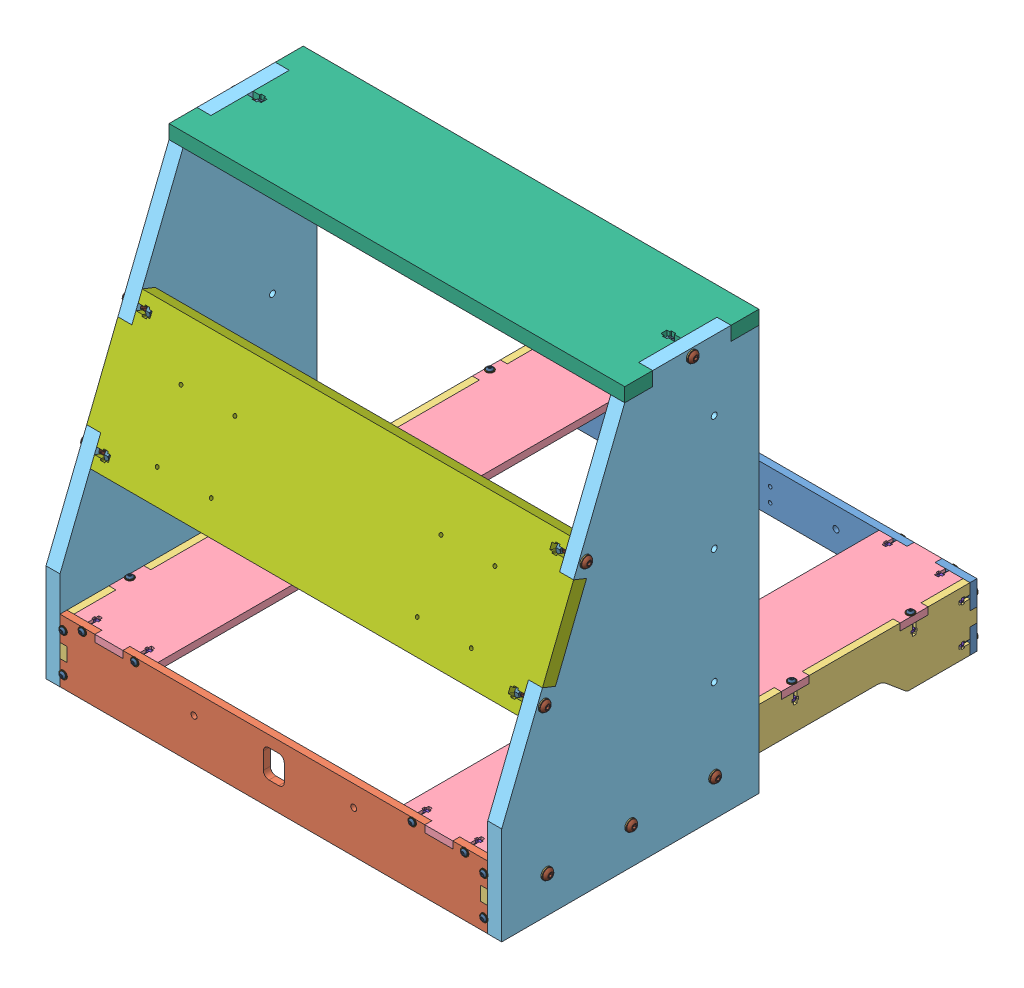
SolidWorks assembly F-101, configuration Default. Lengths in mm.
Overall size (422.07 381 449.23).
118 component instances, 14 part files, 108 mates.
Components (placement in the parent):
- F-001-1: F-001 [Default] at (282.1079 170.2478 108.7947) size (388.62 57.15 6.35)
- F-002-1: F-002 [Default] at (282.1079 170.2478 546.9447) size (388.62 57.15 6.35)
- F-003_rB-2: F-003_rB [Default] at (282.1079 170.2478 546.9447) x (-1 0 0) z (0 0 -1) size (6.35 57.15 444.5)
- F-003_rB-3: F-003_rB [Default] at (-100.1621 170.2478 546.9447) x (-1 0 0) z (0 0 -1) size (6.35 57.15 444.5)
- F-004-1: F-004 [Default] at (282.1079 278.1978 546.9447) x (1 0 0) z (0 0 -1) size (82.55 6.35 444.5)
- F-004-2: F-004 [Default] at (-93.8121 170.2478 546.9447) x (-1 0 0) z (0 0 -1) size (82.55 6.35 444.5)
- F-005_rB-1: F-005_rB [Default] at (-100.1621 170.1301 535.493) x (-1 0 0) z (0 0 -1) size (12.7 381 233.68)
- F-005_rB-2: F-005_rB [Default] at (301.1579 170.1301 535.493) x (-1 0 0) z (0 0 -1) size (12.7 381 233.68)
- F-006_rB-1: F-006_rB [Default] at (-100.1621 538.4301 657.413) size (414.02 12.7 121.92)
- F-007_rB-1: F-007_rB [Default] at (94.1479 382.2218 706.218) x (1 0 0) z (0 0.371391 0.928477) size (414.02 127 12.7)
- H-020-1: H-020 [92497A200] at (267.8204 224.2228 337.2447) size (5.5 6.35 2.78)
- H-024-1: H-024 [98269A420] at (267.8204 224.2228 324.6947) x (-0.923728 -0.383049 0) z (0 0 -1) size (7 7 0.6)
- H-022-1: H-022 [91239A120] at (267.8204 224.2228 322.4447) x (-0.923728 -0.383049 0) z (0 0 -1) size (5.7 5.7 18)
- H-022-2: H-022 [91239A120] at (220.1954 224.2228 322.4447) x (-0.923728 -0.383049 0) z (0 0 -1) size (5.7 5.7 18)
- H-024-2: H-024 [98269A420] at (220.1954 224.2228 324.6947) x (-0.923728 -0.383049 0) z (0 0 -1) size (7 7 0.6)
- H-022-3: H-022 [91239A120] at (285.2829 216.2853 322.4447) x (-0.923728 -0.383049 0) z (0 0 -1) size (5.7 5.7 18)
- H-022-4: H-022 [91239A120] at (285.2829 181.3603 322.4447) x (-0.923728 -0.383049 0) z (0 0 -1) size (5.7 5.7 18)
- H-024-3: H-024 [98269A420] at (285.2829 216.2853 324.6947) x (-0.923728 -0.383049 0) z (0 0 -1) size (7 7 0.6)
- H-024-4: H-024 [98269A420] at (285.2829 181.3603 324.6947) x (-0.923728 -0.383049 0) z (0 0 -1) size (7 7 0.6)
- H-020-2: H-020 [92497A200] at (220.1954 224.2228 337.2447) x (0.5 0.866025 0) z (0 0 1) size (5.5 6.35 2.78)
- H-020-3: H-020 [92497A200] at (285.2829 216.2853 337.2447) x (0 -1 0) z (0 0 1) size (5.5 6.35 2.78)
- H-020-4: H-020 [92497A200] at (285.2829 181.3603 337.2447) x (0 -1 0) z (0 0 1) size (5.5 6.35 2.78)
- H-024-5: H-024 [98269A420] at (285.2829 227.3978 381.8447) x (-0.130134 0 -0.991496) z (0 1 0) size (7 7 0.6)
- H-020-5: H-020 [92497A200] at (285.2829 214.8478 381.8447) x (-0.866025 0 0.5) z (0 1 0) size (5.5 6.35 2.78)
- H-020-6: H-020 [92497A200] at (285.2829 214.8478 489.7947) x (-0.866025 0 -0.5) z (0 -1 0) size (5.5 6.35 2.78)
- H-024-6: H-024 [98269A420] at (285.2829 227.9978 489.7947) x (-0.923728 0 0.383049) z (0 -1 0) size (7 7 0.6)
- H-022-5: H-022 [91239A120] at (285.2829 229.6478 489.7947) x (-0.293351 0 -0.956005) z (0 1 0) size (5.7 5.7 18)
- H-022-6: H-022 [91239A120] at (285.2829 229.6478 381.8447) x (-0.923728 0 -0.383049) z (0 1 0) size (5.7 5.7 18)
- H-022-13: H-022 [91239A120] at (285.2829 229.6478 597.7447) x (-0.293351 0 -0.956005) z (0 1 0) size (5.7 5.7 18)
- H-022-14: H-022 [91239A120] at (285.2829 229.6478 708.8697) x (-0.293351 0 -0.956005) z (0 1 0) size (5.7 5.7 18)
- H-024-13: H-024 [98269A420] at (285.2829 227.9978 597.7447) x (-0.923728 0 0.383049) z (0 -1 0) size (7 7 0.6)
- H-024-14: H-024 [98269A420] at (285.2829 227.9978 708.8697) x (-0.923728 0 0.383049) z (0 -1 0) size (7 7 0.6)
- H-020-13: H-020 [92497A200] at (285.2829 214.8478 597.7447) x (-0.866025 0 0.5) z (0 -1 0) size (5.5 6.35 2.78)
- H-020-14: H-020 [92497A200] at (285.2829 214.8478 708.8697) x (0 0 -1) z (0 -1 0) size (5.5 6.35 2.78)
- H-009-1: H-009 [91239A234] at (305.0079 203.9968 728.533) x (0 0 -1) z (1 0 0) size (9.5 9.5 28.3)
- H-011-1: H-011 [93475A240] at (301.1579 203.9968 728.533) x (0 0 -1) z (1 0 0) size (10 10 1.1)
- H-012-1: H-012 [90576A104] at (282.1079 203.9968 728.533) x (0 1 0) z (0 0 1) size (8 5.15 9.24)
- H-020-7: H-020 [92497A200] at (267.8204 224.2228 756.6447) x (1 0 0) z (0 0 -1) size (5.5 6.35 2.78)
- H-024-7: H-024 [98269A420] at (267.8204 224.2228 769.7947) x (-0.923728 -0.383049 0) z (0 0 -1) size (7 7 0.6)
- H-022-7: H-022 [91239A120] at (267.8204 224.2228 771.4447) x (-0.923728 -0.383049 0) z (0 0 1) size (5.7 5.7 18)
- H-022-8: H-022 [91239A120] at (220.1954 224.2228 771.4447) x (-0.923728 -0.383049 0) z (0 0 1) size (5.7 5.7 18)
- H-024-8: H-024 [98269A420] at (220.1954 224.2228 769.7947) x (-0.923728 -0.383049 0) z (0 0 -1) size (7 7 0.6)
- H-022-9: H-022 [91239A120] at (285.2829 216.2853 771.4447) x (-0.923728 -0.383049 0) z (0 0 1) size (5.7 5.7 18)
- H-022-10: H-022 [91239A120] at (285.2829 181.3603 771.4447) x (-0.923728 -0.383049 0) z (0 0 1) size (5.7 5.7 18)
- H-024-9: H-024 [98269A420] at (285.2829 216.2853 769.7947) x (-0.923728 -0.383049 0) z (0 0 -1) size (7 7 0.6)
- H-024-10: H-024 [98269A420] at (285.2829 181.3603 769.7947) x (-0.923728 -0.383049 0) z (0 0 -1) size (7 7 0.6)
- H-020-8: H-020 [92497A200] at (220.1954 224.2228 756.6621) x (0.5 0.866025 0) z (0 0 1) size (5.5 6.35 2.78)
- H-020-9: H-020 [92497A200] at (285.2829 216.2853 756.6621) x (0 1 0) z (0 0 1) size (5.5 6.35 2.78)
- H-020-10: H-020 [92497A200] at (285.2829 181.3603 756.6621) x (0 1 0) z (0 0 1) size (5.5 6.35 2.78)
- H-012-2: H-012 [90576A104] at (282.1079 203.9968 652.333) x (0 1 0) z (0 0 1) size (8 5.15 9.24)
- H-012-3: H-012 [90576A104] at (282.1079 203.9968 576.133) x (0 1 0) z (0 0 1) size (8 5.15 9.24)
- H-011-2: H-011 [93475A240] at (301.1579 203.9968 652.333) x (0 0 -1) z (1 0 0) size (10 10 1.1)
- H-011-3: H-011 [93475A240] at (301.1579 203.9968 576.133) x (0 0 -1) z (1 0 0) size (10 10 1.1)
- H-009-2: H-009 [91239A234] at (305.0079 203.9968 652.333) x (0 0 -1) z (1 0 0) size (9.5 9.5 28.3)
- H-009-3: H-009 [91239A234] at (305.0079 203.9968 576.133) x (0 0 -1) z (1 0 0) size (9.5 9.5 28.3)
- H-009-4: H-009 [91239A234] at (305.0079 337.4135 730.9804) x (0 0 -1) z (1 0 0) size (9.5 9.5 28.3)
- H-009-5: H-009 [91239A234] at (305.0079 431.7468 693.2471) x (0 0 -1) z (1 0 0) size (9.5 9.5 28.3)
- H-009-6: H-009 [91239A234] at (305.0079 544.7801 596.453) x (0 0 -1) z (1 0 0) size (9.5 9.5 28.3)
- H-011-4: H-011 [93475A240] at (301.1579 337.4135 730.9804) x (0 0 -1) z (1 0 0) size (10 10 1.1)
- H-011-5: H-011 [93475A240] at (301.1579 431.7468 693.2471) x (0 0 -1) z (1 0 0) size (10 10 1.1)
- H-011-6: H-011 [93475A240] at (301.1579 544.7801 596.453) x (0 0 -1) z (1 0 0) size (10 10 1.1)
- H-016-1: H-016 [92497A300] at (280.5079 431.7468 693.2471) x (0 -0.785872 -0.618389) z (1 0 0) size (8 9.24 4.46)
- H-016-2: H-016 [92497A300] at (280.5079 337.4135 730.9804) x (0 -0.142605 0.98978) z (-1 0 0) size (8 9.24 4.46)
- H-016-3: H-016 [92497A300] at (280.5079 544.7801 596.453) x (0 -0.866025 -0.5) z (1 0 0) size (8 9.24 4.46)
- H-012-4: H-012 [90576A104] at (-93.8121 203.9968 728.533) x (0 -1 0) z (0 0 1) size (8 5.15 9.24)
- H-011-7: H-011 [93475A240] at (-113.9621 203.9968 728.533) x (0 0 -1) z (1 0 0) size (10 10 1.1)
- H-009-7: H-009 [91239A234] at (-116.7121 203.9968 728.533) x (0 0 -1) z (-1 0 0) size (9.5 9.5 28.3)
- H-020-15: H-020 [92497A200] at (-79.5246 224.2228 337.2447) x (-1 0 0) z (0 0 1) size (5.5 6.35 2.78)
- H-024-15: H-024 [98269A420] at (-79.5246 224.2228 324.0947) x (0.923728 -0.383049 0) z (0 0 1) size (7 7 0.6)
- H-022-15: H-022 [91239A120] at (-79.5246 224.2228 322.4447) x (0.923728 -0.383049 0) z (0 0 -1) size (5.7 5.7 18)
- H-022-16: H-022 [91239A120] at (-31.8996 224.2228 322.4447) x (0.923728 -0.383049 0) z (0 0 -1) size (5.7 5.7 18)
- H-024-16: H-024 [98269A420] at (-31.8996 224.2228 324.0947) x (0.923728 -0.383049 0) z (0 0 1) size (7 7 0.6)
- H-022-17: H-022 [91239A120] at (-96.9871 216.2853 322.4447) x (0.923728 -0.383049 0) z (0 0 -1) size (5.7 5.7 18)
- H-022-18: H-022 [91239A120] at (-96.9871 181.3603 322.4447) x (0.923728 -0.383049 0) z (0 0 -1) size (5.7 5.7 18)
- H-024-17: H-024 [98269A420] at (-96.9871 216.2853 324.0947) x (0.923728 -0.383049 0) z (0 0 1) size (7 7 0.6)
- H-024-18: H-024 [98269A420] at (-96.9871 181.3603 324.0947) x (0.923728 -0.383049 0) z (0 0 1) size (7 7 0.6)
- H-020-16: H-020 [92497A200] at (-31.8996 224.2228 337.2272) x (-0.5 0.866025 0) z (0 0 -1) size (5.5 6.35 2.78)
- H-020-17: H-020 [92497A200] at (-96.9871 216.2853 337.2272) x (0 1 0) z (0 0 -1) size (5.5 6.35 2.78)
- H-020-18: H-020 [92497A200] at (-96.9871 181.3603 337.2272) x (0 1 0) z (0 0 -1) size (5.5 6.35 2.78)
- H-016-4: H-016 [92497A300] at (-92.2121 544.7801 596.453) x (0 0.866025 0.5) z (-1 0 0) size (8 9.24 4.46)
- H-024-19: H-024 [98269A420] at (-96.9871 227.9978 381.8447) x (0.130134 0 -0.991496) z (0 -1 0) size (7 7 0.6)
- H-020-19: H-020 [92497A200] at (-96.9871 214.8303 381.8447) x (0.866025 0 0.5) z (0 -1 0) size (5.5 6.35 2.78)
- H-020-20: H-020 [92497A200] at (-96.9871 214.8653 489.7947) x (0.866025 0 -0.5) z (0 1 0) size (5.5 6.35 2.78)
- H-024-20: H-024 [98269A420] at (-96.9871 227.3978 489.7947) x (0.923728 0 0.383049) z (0 1 0) size (7 7 0.6)
- H-022-19: H-022 [91239A120] at (-96.9871 229.6478 489.7947) x (-0.293351 0 0.956005) z (0 1 0) size (5.7 5.7 18)
- H-022-20: H-022 [91239A120] at (-96.9871 229.6478 381.8447) x (0.923728 0 -0.383049) z (0 1 0) size (5.7 5.7 18)
- H-022-21: H-022 [91239A120] at (-96.9871 229.6478 597.7447) x (-0.293351 0 0.956005) z (0 1 0) size (5.7 5.7 18)
- H-022-22: H-022 [91239A120] at (-96.9871 229.6478 708.8697) x (-0.293351 0 0.956005) z (0 1 0) size (5.7 5.7 18)
- H-024-21: H-024 [98269A420] at (-96.9871 227.3978 597.7447) x (0.923728 0 0.383049) z (0 1 0) size (7 7 0.6)
- H-024-22: H-024 [98269A420] at (-96.9871 227.3978 708.8697) x (0.923728 0 0.383049) z (0 1 0) size (7 7 0.6)
- H-020-21: H-020 [92497A200] at (-96.9871 214.8653 597.7447) x (0.866025 0 0.5) z (0 1 0) size (5.5 6.35 2.78)
- H-020-22: H-020 [92497A200] at (-96.9871 214.8653 708.8697) x (0 0 1) z (0 1 0) size (5.5 6.35 2.78)
- H-009-8: H-009 [91239A234] at (-116.7121 337.4135 730.9804) x (0 0 -1) z (-1 0 0) size (9.5 9.5 28.3)
- H-009-9: H-009 [91239A234] at (-116.7121 431.7468 693.2471) x (0 0 -1) z (-1 0 0) size (9.5 9.5 28.3)
- H-009-10: H-009 [91239A234] at (-116.7121 544.7801 596.453) x (0 0 -1) z (-1 0 0) size (9.5 9.5 28.3)
- H-011-8: H-011 [93475A240] at (-113.9621 337.4135 730.9804) x (0 0 -1) z (1 0 0) size (10 10 1.1)
- H-011-9: H-011 [93475A240] at (-113.9621 431.7468 693.2471) x (0 0 -1) z (1 0 0) size (10 10 1.1)
- H-011-10: H-011 [93475A240] at (-113.9621 544.7801 596.453) x (0 0 -1) z (1 0 0) size (10 10 1.1)
- H-016-5: H-016 [92497A300] at (-92.2121 431.7468 693.2471) x (0 0.785872 0.618389) z (-1 0 0) size (8 9.24 4.46)
- H-016-6: H-016 [92497A300] at (-92.2121 337.4135 730.9804) x (0 0.142605 -0.98978) z (1 0 0) size (8 9.24 4.46)
- H-012-5: H-012 [90576A104] at (-93.8121 203.9968 652.333) x (0 -1 0) z (0 0 1) size (8 5.15 9.24)
- H-012-6: H-012 [90576A104] at (-93.8121 203.9968 576.133) x (0 -1 0) z (0 0 1) size (8 5.15 9.24)
- H-011-11: H-011 [93475A240] at (-113.9621 203.9968 652.333) x (0 0 -1) z (1 0 0) size (10 10 1.1)
- H-011-12: H-011 [93475A240] at (-113.9621 203.9968 576.133) x (0 0 -1) z (1 0 0) size (10 10 1.1)
- H-009-11: H-009 [91239A234] at (-116.7121 203.9968 652.333) x (0 0 -1) z (-1 0 0) size (9.5 9.5 28.3)
- H-009-12: H-009 [91239A234] at (-116.7121 203.9968 576.133) x (0 0 -1) z (-1 0 0) size (9.5 9.5 28.3)
- H-020-23: H-020 [92497A200] at (-79.5246 224.2228 756.6447) x (-1 0 0) z (0 0 -1) size (5.5 6.35 2.78)
- H-024-23: H-024 [98269A420] at (-79.5246 224.2228 769.1947) x (0.923728 -0.383049 0) z (0 0 1) size (7 7 0.6)
- H-022-23: H-022 [91239A120] at (-79.5246 224.2228 771.4447) x (0.923728 -0.383049 0) z (0 0 1) size (5.7 5.7 18)
- H-022-24: H-022 [91239A120] at (-31.8996 224.2228 771.4447) x (0.923728 -0.383049 0) z (0 0 1) size (5.7 5.7 18)
- H-024-24: H-024 [98269A420] at (-31.8996 224.2228 769.1947) x (0.923728 -0.383049 0) z (0 0 1) size (7 7 0.6)
- H-022-25: H-022 [91239A120] at (-96.9871 216.2853 771.4447) x (0.923728 -0.383049 0) z (0 0 1) size (5.7 5.7 18)
- H-022-26: H-022 [91239A120] at (-96.9871 181.3603 771.4447) x (0.923728 -0.383049 0) z (0 0 1) size (5.7 5.7 18)
- H-024-25: H-024 [98269A420] at (-96.9871 216.2853 769.1947) x (0.923728 -0.383049 0) z (0 0 1) size (7 7 0.6)
- H-024-26: H-024 [98269A420] at (-96.9871 181.3603 769.1947) x (0.923728 -0.383049 0) z (0 0 1) size (7 7 0.6)
- H-020-24: H-020 [92497A200] at (-31.8996 224.2228 756.6447) x (-0.5 0.866025 0) z (0 0 -1) size (5.5 6.35 2.78)
- H-020-25: H-020 [92497A200] at (-96.9871 216.2853 756.6447) x (0 -1 0) z (0 0 -1) size (5.5 6.35 2.78)
- H-020-26: H-020 [92497A200] at (-96.9871 181.3603 756.6447) x (0 -1 0) z (0 0 -1) size (5.5 6.35 2.78)
Mates (geometry in assembly coordinates):
- Coincident52: coincident aligned: plane of F-001-1 through (-100.1621 192.4728 324.6947) normal (-1 0 0); plane of F-003_rB-3 through (-100.1621 175.3278 386.3457) normal (-1 0 0)
- Coincident53: coincident aligned: plane of F-001-1 through (-38.511 175.3278 324.6947) normal (0 0 -1); plane of F-003_rB-3 through (-93.8121 205.1728 324.6947) normal (0 0 -1)
- Coincident54: coincident aligned: plane of F-001-1 through (-68.4121 227.3978 324.6947) normal (0 1 0); plane of F-003_rB-3 through (-93.8121 227.3978 369.1447) normal (0 1 0)
- Coincident55: coincident aligned: plane of F-002-1 through (282.1079 170.2478 769.1947) normal (0 0 1); plane of F-003_rB-3 through (-93.8121 192.4728 769.1947) normal (0 0 1)
- Coincident56: coincident aligned: plane of F-002-1 through (288.4579 192.4728 769.1947) normal (1 0 0); plane of F-003_rB-2 through (288.4579 175.3278 386.3457) normal (1 0 0)
- Coincident57: coincident aligned: plane of F-003_rB-2 through (288.4579 192.4728 769.1947) normal (0 0 1); plane of F-002-1 through (282.1079 170.2478 769.1947) normal (0 0 1)
- Coincident58: coincident aligned: plane of F-002-1 through (256.7079 227.3978 769.1947) normal (0 1 0); plane of F-003_rB-2 through (288.4579 227.3978 762.8447) normal (0 1 0)
- Coincident59: coincident aligned: plane of F-002-1 through (-100.1621 227.3978 769.1947) normal (0 1 0); plane of F-004-1 through (282.1079 227.3978 546.9447) normal (0 1 0)
- Coincident61: coincident aligned: plane of F-002-1 through (282.1079 170.2478 769.1947) normal (0 0 1); plane of F-004-1 through (-68.4121 221.0478 769.1947) normal (0 0 1)
- Coincident62: coincident aligned: plane of F-003_rB-3 through (-100.1621 175.3278 386.3457) normal (-1 0 0); plane of F-004-1 through (-100.1621 221.0478 369.1447) normal (-1 0 0)
- Coincident69: coincident aligned: plane of F-001-1 through (-38.511 175.3278 324.6947) normal (0 0 -1); plane of F-004-2 through (231.3079 227.3978 324.6947) normal (0 0 -1)
- Coincident71: coincident anti-aligned: plane of F-003_rB-3 through (-93.8121 221.0478 394.5447) normal (0 1 0); plane of F-004-1 through (282.1079 221.0478 546.9447) normal (0 -1 0)
- Coincident72: coincident aligned: plane of F-001-1 through (231.3079 227.3978 324.6947) normal (0 1 0); plane of F-004-2 through (-93.8121 227.3978 546.9447) normal (0 1 0)
- Coincident73: coincident aligned: plane of F-003_rB-2 through (288.4579 175.3278 386.3457) normal (1 0 0); plane of F-004-2 through (288.4579 227.3978 585.0447) normal (1 0 0)
- Coincident74: coincident aligned: plane of F-002-1 through (-100.1621 205.1728 769.1947) normal (-1 0 0); plane of F-003_rB-3 through (-100.1621 175.3278 386.3457) normal (-1 0 0)
- Coincident75: coincident anti-aligned: plane of F-003_rB-3 through (-100.1621 175.3278 386.3457) normal (-1 0 0); plane of F-005_rB-1 through (-100.1621 170.1301 535.493) normal (1 0 0)
- Concentric15: concentric anti-aligned: circle of F-003_rB-3; circle of F-005_rB-1
- Parallel4: parallel aligned: plane of F-002-1 through (282.1079 170.2478 769.1947) normal (0 0 1); plane of F-005_rB-1 through (-112.8621 170.1301 769.173) normal (0 0 1)
- Coincident79: coincident anti-aligned: circle of F-003_rB-2; circle of F-005_rB-2
- Parallel5: parallel aligned: plane of F-003_rB-2 through (288.4579 170.2478 707.5436) normal (0 -1 0); plane of F-005_rB-2 through (288.4579 170.1301 769.173) normal (0 -1 0)
- Coincident81: coincident aligned: plane of F-005_rB-1 through (-112.8621 170.1301 535.493) normal (0 0 -1); plane of F-006_rB-1 through (-100.1621 551.1301 535.493) normal (0 0 -1)
- Coincident82: coincident aligned: plane of F-005_rB-1 through (-112.8621 551.1301 535.493) normal (0 1 0); plane of F-006_rB-1 through (-100.1621 551.1301 657.413) normal (0 1 0)
- Coincident84: coincident anti-aligned: plane of F-005_rB-1 through (-100.1621 170.1301 535.493) normal (1 0 0); plane of F-006_rB-1 through (-100.1621 551.1301 657.413) normal (-1 0 0)
- Coincident85: coincident aligned: plane of F-005_rB-1 through (-112.8621 170.1301 535.493) normal (-1 0 0); plane of F-007_rB-1 through (-112.8621 351.5635 732.1596) normal (-1 0 0)
- Coincident86: coincident anti-aligned: plane of F-005_rB-1 through (-100.1611 417.5968 692.068) normal (0 0.371391 0.928477); plane of F-007_rB-1 through (94.1479 382.2218 706.218) normal (0 -0.371391 -0.928477)
- Coincident87: coincident anti-aligned: plane of F-005_rB-1 through (-100.1611 417.5968 692.068) normal (0 -0.928477 0.371391); plane of F-007_rB-1 through (-112.8621 422.3134 703.8596) normal (0 0.928477 -0.371391)
- Concentric16: concentric aligned: circle of H-024-1; circle of H-022-1
- Coincident88: coincident anti-aligned: plane of H-024-1 through (267.8204 224.2228 324.0947) normal (0 0 -1); plane of H-022-1 through (268.9121 221.5902 324.0947) normal (0 0 1)
- Concentric17: concentric anti-aligned: circle of F-001-1; circle of H-024-1
- Coincident89: coincident anti-aligned: plane of F-001-1 through (-38.511 175.3278 324.6947) normal (0 0 -1); plane of H-024-1 through (267.8204 224.2228 324.6947) normal (0 0 1)
- Coincident90: coincident anti-aligned: plane of F-004-2 through (270.6704 227.3978 336.0447) normal (0 0 1); plane of H-020-1 through (265.0704 225.8105 336.0447) normal (0 0 -1)
- Concentric18: concentric aligned: circle of H-020-1; circle of H-024-1
- Concentric19: concentric aligned: circle of H-022-2; circle of H-024-2
- Coincident91: coincident anti-aligned: plane of H-022-2 through (221.2871 221.5902 324.0947) normal (0 0 1); plane of H-024-2 through (220.1954 224.2228 324.0947) normal (0 0 -1)
- Concentric20: concentric anti-aligned: circle of F-001-1; circle of H-024-2
- Coincident92: coincident anti-aligned: plane of F-001-1 through (-38.511 175.3278 324.6947) normal (0 0 -1); plane of H-024-2 through (220.1954 224.2228 324.6947) normal (0 0 1)
- Concentric21: concentric aligned: circle of H-022-4; circle of H-024-4
- Coincident93: coincident anti-aligned: plane of H-022-4 through (286.3746 178.7277 324.0947) normal (0 0 1); plane of H-024-4 through (285.2829 181.3603 324.0947) normal (0 0 -1)
- Concentric22: concentric anti-aligned: circle of F-001-1; circle of H-024-4
- Coincident94: coincident anti-aligned: plane of F-001-1 through (-38.511 175.3278 324.6947) normal (0 0 -1); plane of H-024-4 through (285.2829 181.3603 324.6947) normal (0 0 1)
- Concentric23: concentric aligned: circle of H-022-3; circle of H-024-3
- Coincident95: coincident anti-aligned: plane of H-022-3 through (286.3746 213.6527 324.0947) normal (0 0 1); plane of H-024-3 through (285.2829 216.2853 324.0947) normal (0 0 -1)
- Concentric24: concentric anti-aligned: circle of F-001-1; circle of H-024-3
- Coincident96: coincident anti-aligned: plane of F-001-1 through (-38.511 175.3278 324.6947) normal (0 0 -1); plane of H-024-3 through (285.2829 216.2853 324.6947) normal (0 0 1)
- Concentric25: concentric aligned: circle of H-024-4; circle of H-020-4
- Parallel6: parallel anti-aligned: plane of F-003_rB-2 through (288.4579 178.5103 338.5447) normal (0 1 0); plane of H-020-4 through (283.6952 178.6103 338.4447) normal (0 -1 0)
- Coincident98: coincident anti-aligned: plane of F-003_rB-2 through (288.4579 178.5103 336.0447) normal (0 0 1); plane of H-020-4 through (286.8707 184.1103 336.0447) normal (0 0 -1)
- Concentric26: concentric aligned: circle of H-024-3; circle of H-020-3
- Parallel7: parallel anti-aligned: plane of F-003_rB-2 through (288.4579 213.4353 338.5447) normal (0 1 0); plane of H-020-3 through (283.6952 213.5353 338.4447) normal (0 -1 0)
- Coincident100: coincident anti-aligned: plane of F-003_rB-2 through (288.4579 213.4353 336.0447) normal (0 0 1); plane of H-020-3 through (286.8707 219.0353 336.0447) normal (0 0 -1)
- Concentric27: concentric aligned: circle of H-024-2; circle of H-020-2
- Coincident101: coincident anti-aligned: plane of F-004-2 through (218.5454 227.3978 336.0447) normal (0 0 1); plane of H-020-2 through (217.4454 222.6351 336.0447) normal (0 0 -1)
- Parallel8: parallel anti-aligned: plane of F-004-2 through (217.3454 227.3978 336.0447) normal (1 0 0); plane of H-020-2 through (217.4454 225.8105 338.4447) normal (-1 0 0)
- Concentric28: concentric aligned: circle of H-024-5; circle of H-022-6
- Coincident103: coincident anti-aligned: plane of H-024-5 through (285.2829 227.9978 381.8447) normal (0 1 0); plane of H-022-6 through (286.3746 227.9978 379.212) normal (0 -1 0)
- Concentric29: concentric anti-aligned: circle of F-004-2; circle of H-024-5
- Coincident104: coincident anti-aligned: plane of F-004-2 through (-93.8121 227.3978 546.9447) normal (0 1 0); plane of H-024-5 through (285.2829 227.3978 381.8447) normal (0 -1 0)
- Concentric30: concentric anti-aligned: circle of H-024-5; circle of H-020-5
- Parallel9: parallel anti-aligned: plane of F-003_rB-2 through (288.4579 216.0478 384.6947) normal (0 0 -1); plane of H-020-5 through (283.6952 216.0478 384.5947) normal (0 0 1)
- Coincident106: coincident anti-aligned: plane of F-003_rB-2 through (288.4579 216.0478 383.4947) normal (0 -1 0); plane of H-020-5 through (288.4584 216.0478 381.8447) normal (0 1 0)
- Concentric31: concentric aligned: cylinder of H-024-6 through (285.2829 227.3978 489.7947) axis (0 1 0) radius 1.6; circle of H-022-5
- Coincident107: coincident anti-aligned: plane of H-024-6 through (285.2829 227.9978 489.7947) normal (0 1 0); plane of H-022-5 through (288.0076 227.9978 488.9586) normal (0 -1 0)
- Concentric32: concentric aligned: circle of F-004-2; circle of H-024-6
- Coincident108: coincident anti-aligned: plane of F-004-2 through (-93.8121 227.3978 546.9447) normal (0 1 0); plane of H-024-6 through (285.2829 227.3978 489.7947) normal (0 -1 0)
- Concentric33: concentric anti-aligned: circle of H-020-6; circle of H-022-5
- Parallel10: parallel anti-aligned: plane of F-003_rB-2 through (288.4579 213.5478 486.9447) normal (0 0 1); plane of H-020-6 through (283.6952 213.6478 487.0447) normal (0 0 -1)
- Coincident110: coincident anti-aligned: plane of F-003_rB-2 through (288.4579 216.0478 486.9447) normal (0 -1 0); plane of H-020-6 through (288.4584 216.0478 489.7947) normal (0 1 0)
- Concentric34: concentric anti-aligned: circle of H-022-13; circle of H-024-13
- Coincident111: coincident anti-aligned: plane of H-022-13 through (288.0076 227.9978 596.9086) normal (0 -1 0); plane of H-024-13 through (285.2829 227.9978 597.7447) normal (0 1 0)
- Coincident112: coincident anti-aligned: plane of F-004-2 through (-93.8121 227.3978 546.9447) normal (0 1 0); plane of H-024-13 through (285.2829 227.3978 597.7447) normal (0 -1 0)
- Concentric35: concentric aligned: circle of F-004-2; circle of H-024-13
- Concentric36: concentric anti-aligned: circle of H-022-13; circle of H-020-13
- Coincident113: coincident anti-aligned: plane of F-003_rB-2 through (288.4579 216.0478 599.3947) normal (0 -1 0); plane of H-020-13 through (286.8707 216.0478 594.9947) normal (0 1 0)
- Parallel11: parallel anti-aligned: plane of F-003_rB-2 through (288.4579 216.0478 600.5947) normal (0 0 -1); plane of H-020-13 through (286.8707 213.6478 600.4947) normal (0 0 1)
- Concentric37: concentric anti-aligned: circle of H-022-14; circle of H-024-14
- Coincident115: coincident anti-aligned: plane of H-022-14 through (288.0076 227.9978 708.0336) normal (0 -1 0); plane of H-024-14 through (285.2829 227.9978 708.8697) normal (0 1 0)
- Coincident116: coincident anti-aligned: plane of F-004-2 through (-93.8121 227.3978 546.9447) normal (0 1 0); plane of H-024-14 through (285.2829 227.3978 708.8697) normal (0 -1 0)
- Concentric38: concentric aligned: circle of F-004-2; circle of H-024-14
- Concentric39: concentric anti-aligned: circle of H-022-14; circle of H-020-14
- Parallel12: parallel aligned: plane of F-003_rB-2 through (288.4579 216.0478 711.7197) normal (0 0 -1); plane of H-020-14 through (283.6952 213.6478 706.1197) normal (0 0 -1)
- Coincident118: coincident anti-aligned: plane of F-003_rB-2 through (288.4579 216.0478 710.5197) normal (0 -1 0); plane of H-020-14 through (286.8707 216.0478 711.6197) normal (0 1 0)
- Concentric40: concentric aligned: circle of H-009-1; circle of H-011-1
- Coincident119: coincident anti-aligned: plane of H-009-1 through (302.2579 199.2468 728.533) normal (-1 0 0); plane of H-011-1 through (302.2579 203.9968 728.533) normal (1 0 0)
- Concentric41: concentric aligned: circle of F-005_rB-2; circle of H-011-1
- Coincident120: coincident anti-aligned: plane of F-005_rB-2 through (301.1579 170.1301 535.493) normal (1 0 0); plane of H-011-1 through (301.1579 203.9968 728.533) normal (-1 0 0)
- Concentric42: concentric anti-aligned: circle of F-003_rB-2; circle of H-012-1
- Coincident121: coincident anti-aligned: plane of F-003_rB-2 through (282.1079 175.3278 386.3457) normal (-1 0 0); plane of H-012-1 through (282.1079 199.9968 721.6048) normal (1 0 0)
- Coincident122: coincident anti-aligned: plane of H-009-6 through (302.2579 540.0301 596.453) normal (-1 0 0); plane of H-011-6 through (302.2579 544.7801 596.453) normal (1 0 0)
- Concentric43: concentric aligned: circle of H-009-6; circle of H-011-6
- Coincident123: coincident anti-aligned: plane of F-005_rB-2 through (301.1579 170.1301 535.493) normal (1 0 0); plane of H-011-6 through (301.1579 544.7801 596.453) normal (-1 0 0)
- Concentric44: concentric anti-aligned: cylinder of F-005_rB-2 through (301.1589 544.7801 596.453) axis (-1 0 0) radius 2.7; circle of H-011-6
- Concentric45: concentric anti-aligned: circle of H-009-6; circle of H-016-3
- Parallel13: parallel anti-aligned: plane of F-006_rB-1 through (278.4079 529.3069 592.378) normal (0 0 1); plane of H-016-3 through (282.5079 542.4707 592.453) normal (0 0 -1)
- Coincident125: coincident anti-aligned: plane of F-006_rB-1 through (282.5079 529.3069 600.528) normal (-1 0 0); plane of H-016-3 through (282.5079 549.3989 596.453) normal (1 0 0)
- Concentric46: concentric aligned: circle of H-009-5; circle of H-011-5
- Coincident126: coincident anti-aligned: plane of H-009-5 through (302.2579 426.9968 693.2471) normal (-1 0 0); plane of H-011-5 through (302.2579 431.7468 693.2471) normal (1 0 0)
- Concentric47: concentric anti-aligned: circle of F-005_rB-2; circle of H-011-5
- Coincident127: coincident anti-aligned: plane of F-005_rB-2 through (301.1579 170.1301 535.493) normal (1 0 0); plane of H-011-5 through (301.1579 431.7468 693.2471) normal (-1 0 0)
- Concentric48: concentric anti-aligned: circle of F-005_rB-2; circle of H-016-1
- Parallel14: parallel anti-aligned: plane of F-007_rB-1 through (278.4079 433.1716 685.837) normal (0 -0.928477 0.371391); plane of H-016-1 through (282.5079 434.603 689.6174) normal (0 0.928477 -0.371391)
- Coincident130: coincident anti-aligned: plane of F-007_rB-1 through (282.5079 425.6045 688.8638) normal (-1 0 0); plane of H-016-1 through (282.5079 436.3184 693.9058) normal (1 0 0)
- Concentric49: concentric aligned: circle of H-009-4; circle of H-011-4
- Coincident131: coincident anti-aligned: plane of H-009-4 through (302.2579 332.6635 730.9804) normal (-1 0 0); plane of H-011-4 through (302.2579 337.4135 730.9804) normal (1 0 0)
- Concentric50: concentric anti-aligned: circle of F-005_rB-2; circle of H-011-4
- Coincident132: coincident anti-aligned: plane of F-005_rB-2 through (301.1579 170.1301 535.493) normal (1 0 0); plane of H-011-4 through (301.1579 337.4135 730.9804) normal (-1 0 0)
- Parallel15: parallel aligned: plane of F-007_rB-1 through (278.4079 331.2713 726.5971) normal (0 0.928477 -0.371391); plane of H-016-2 through (278.5079 341.9851 731.6391) normal (0 0.928477 -0.371391)
- Concentric51: concentric aligned: circle of H-009-4; circle of H-016-2
- Coincident135: coincident anti-aligned: plane of F-007_rB-1 through (282.5079 338.8384 723.5703) normal (-1 0 0); plane of H-016-2 through (282.5079 340.2697 727.3506) normal (1 0 0)
